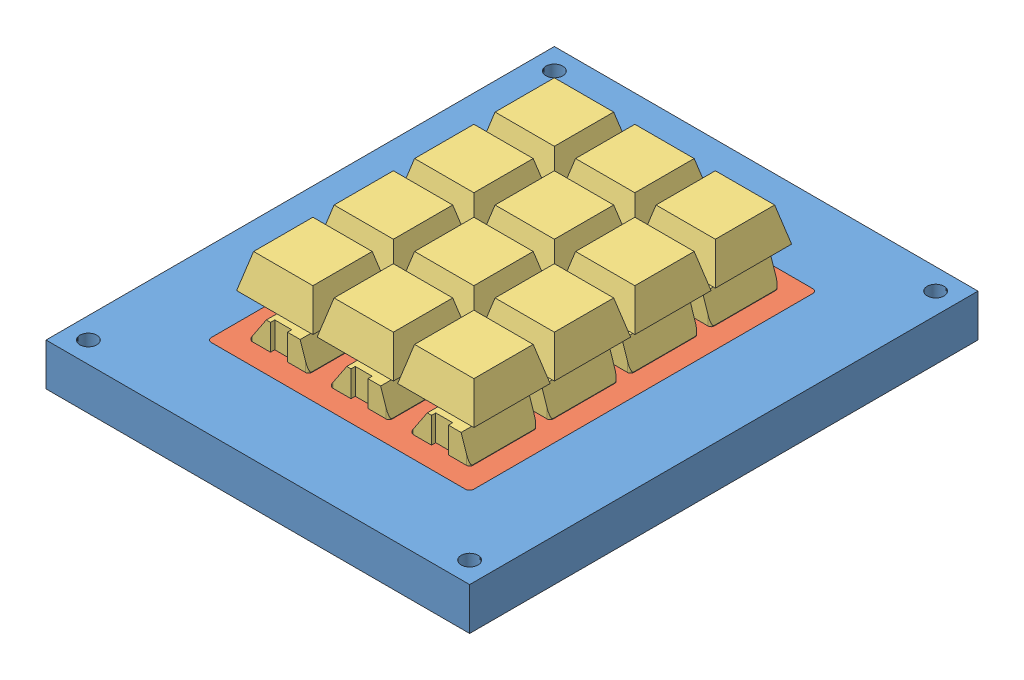
SolidWorks assembly assemblageAccrocheKeyboard, configuration Default. Lengths in mm.
Overall size (85 27.6 120).
15 component instances, 3 part files, 3 mates.
Components (placement in the parent):
- accrocheKeyboard-1: accrocheKeyboard [Default] at (46.8691 57.2795 94.6446) size (85 10 120)
- keyboard-1: keyboard [Default] at (2.8102 -5.5564 65.468) size (62 27.6 82)
  - plaque clavier-1: plaque clavier [Default] at (44.0589 62.8359 29.1766) size (62 10 82)
  - key-1: key [Default] at (25.0589 67.9359 57.1766) size (18 22.5 18)
  - key-2: key [Default] at (44.0589 67.9359 57.1766) size (18 22.5 18)
  - key-3: key [Default] at (63.0589 67.9359 57.1766) size (18 22.5 18)
  - key-4: key [Default] at (25.0589 67.9359 38.1766) size (18 22.5 18)
  - key-5: key [Default] at (44.0589 67.9359 38.1766) size (18 22.5 18)
  - key-6: key [Default] at (63.0589 67.9359 38.1766) size (18 22.5 18)
  - key-7: key [Default] at (25.0589 67.9359 19.1766) size (18 22.5 18)
  - key-8: key [Default] at (44.0589 67.9359 19.1766) size (18 22.5 18)
  - key-9: key [Default] at (63.0589 67.9359 19.1766) size (18 22.5 18)
  - key-10: key [Default] at (44.0589 67.9359 0.1766) size (18 22.5 18)
  - key-11: key [Default] at (25.0589 67.9359 0.1766) size (18 22.5 18)
  - key-12: key [Default] at (63.0589 67.9359 0.1766) size (18 22.5 18)
Mates (geometry in assembly coordinates):
- Coincident2: coincident anti-aligned: plane of accrocheKeyboard-1 through (15.8691 57.2795 135.6446) normal (0 0 -1); plane of keyboard-1/plaque clavier-1 through (15.8691 67.2795 135.6446) normal (0 0 1)
- Coincident3: coincident anti-aligned: plane of accrocheKeyboard-1 through (77.8691 57.2795 135.6446) normal (-1 0 0); plane of keyboard-1/plaque clavier-1 through (77.8691 67.2795 135.6446) normal (1 0 0)
- Coincident4: coincident aligned: plane of accrocheKeyboard-1 through (46.8691 67.2795 94.6446) normal (0 1 0); plane of keyboard-1/plaque clavier-1 through (46.8691 67.2795 94.6446) normal (0 1 0)
